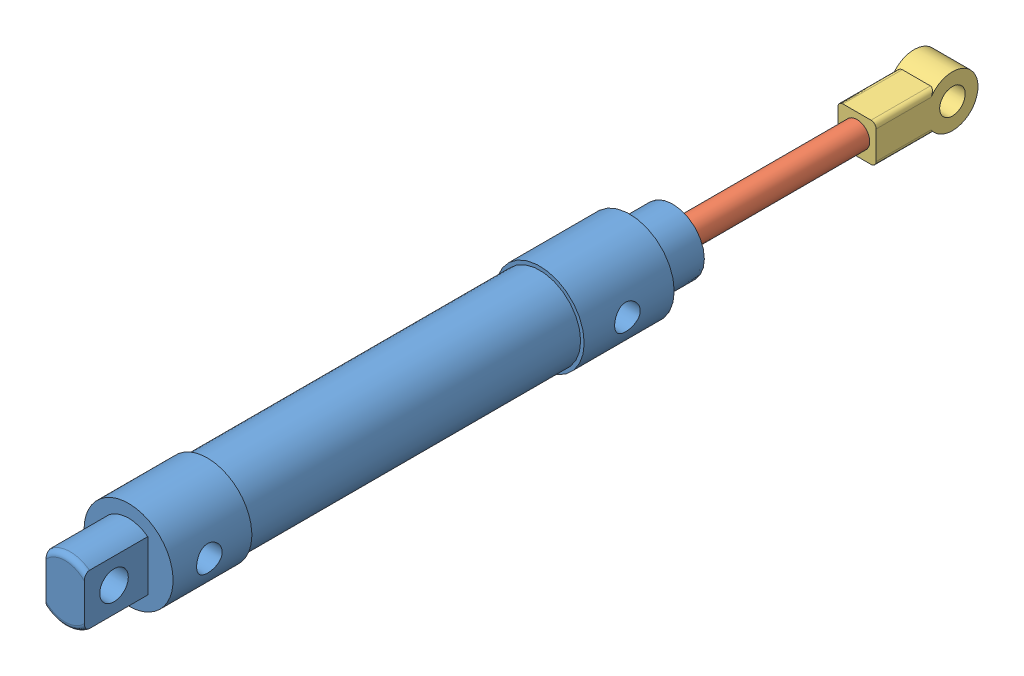
SolidWorks assembly AirCylinder_0.75x2in_Assem, configuration Default. Lengths in mm.
Overall size (22.1 22.1 222.09).
3 component instances, 3 part files, 5 mates.
Components (placement in the parent):
- AirCylinder_0.75x2in-1: AirCylinder_0.75x2in [Default] at origin size (22.1 22.1 151.02)
- AirCylinder_Rod-1: AirCylinder_Rod [Default] at (0 0 -27.9906) x (0.870942 -0.491386 0) z (0 0 -1) size (6.35 6.35 63.5)
- Clevas-1: Clevas [Default] at (-4.7625 0 -97.739) x (0 0 -1) z (0 -1 0) size (25.3 9.53 12.7)
Mates (geometry in assembly coordinates):
- Concentric1: concentric anti-aligned: cylinder of AirCylinder_0.75x2in-1 through (0 0 91.948) axis (0 0 -1) radius 3.175; cylinder of AirCylinder_Rod-1 through (0 0 -91.4906) axis (0 0 1) radius 3.175
- LimitDistance1: limit distance = 58.4706 mm aligned: plane of AirCylinder_0.75x2in-1 through (0 0 -33.02) normal (0 0 -1); plane of AirCylinder_Rod-1 through (0 0 -91.4906) normal (0 0 -1)
- Concentric2: concentric aligned: cylinder of AirCylinder_Rod-1 through (0 0 -91.4906) axis (0 0 1) radius 3.175; cylinder of Clevas-1 through (0 0 -91.4906) axis (0 0 1) radius 3.175
- Coincident1: coincident anti-aligned: plane of AirCylinder_Rod-1 through (0 0 -91.4906) normal (0 0 -1); plane of Clevas-1 through (0 0 -91.4906) normal (0 0 1)
- Parallel1: parallel anti-aligned: plane of AirCylinder_0.75x2in-1 through (-4.7625 -6.2704 117.856) normal (-1 0 0); plane of Clevas-1 through (4.7625 0 -97.739) normal (1 0 0)
